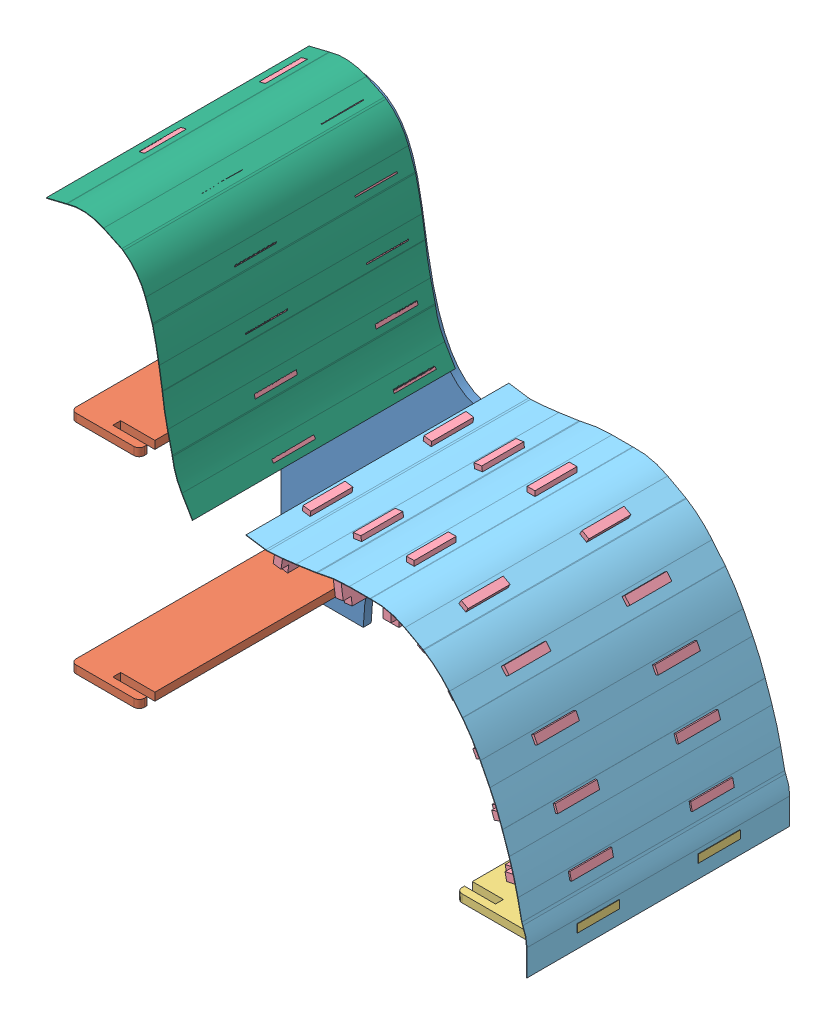
SolidWorks assembly chairA, configuration Default. Lengths in mm.
Overall size (2400 1520.6 565).
21 component instances, 6 part files, 62 mates.
Components (placement in the parent):
- chair-3: chair [Default] at origin size (892.39 905.44 15)
- chair-4: chair [Default] at (0 0 385) size (892.39 905.44 15) (hidden)
- base1-1: base1 [Default] at (0 0 400) size (130 15 430)
- base1-2: base1 [Default] at (0 415 400) size (130 15 430)
- base2-1: base2 [Default] at (0 0 400) size (170 15 430)
- coverSupport-1: coverSupport [Default] x (-1 0 0) z (0 0 -1) size (96.04 34.42 400)
- coverSupport-4: coverSupport [Default] at (34.0048 -123.247 400) x (-0.858521 -0.512778 0) z (0 0 1) size (96.04 34.42 400)
- coverSupport-5: coverSupport [Default] at (52.0991 -142.8628 400) x (-0.777508 -0.628873 0) z (0 0 1) size (96.04 34.42 400)
- coverSupport-7: coverSupport [Default] at (113.3609 -210.8477 400) x (-0.624811 -0.780776 0) z (0 0 1) size (96.04 34.42 400)
- coverSupport-8: coverSupport [Default] at (313.0867 -343.4559 400) x (-0.286022 -0.958223 0) z (0 0 1) size (96.04 34.42 400)
- coverSupport-10: coverSupport [Default] at (656.2813 -398.8647 400) x (0.217755 -0.976003 0) z (0 0 1) size (96.04 34.42 400)
- coverSupport-11: coverSupport [Default] at (674.4375 -392.1959 400) x (0.346446 -0.93807 0) z (0 0 1) size (96.04 34.42 400)
- coverSupport-13: coverSupport [Default] at (317.1284 -414.5841 400) x (0.060853 -0.998147 0) z (0 0 1) size (96.04 34.42 400)
- coverSupport-17: coverSupport [Default] at (-420.7027 22.5592 400) x (-0.737008 -0.675884 0) z (0 0 1) size (96.04 34.42 400)
- coverSupport-18: coverSupport [Default] at (-570.9691 355.3696 400) x (-0.904457 -0.426564 0) z (0 0 1) size (96.04 34.42 400)
- coverSupport-19: coverSupport [Default] at (-605.6475 516.2189 400) x (-0.933201 -0.359355 0) z (0 0 1) size (96.04 34.42 400)
- coverSupport-20: coverSupport [Default] at (-576.6639 460.0885 400) x (-0.85224 -0.523151 0) z (0 0 1) size (96.04 34.42 400)
- coverSupport-21: coverSupport [Default] at (-149.7762 65.2605 400) x (-0.23237 -0.972627 0) z (0 0 1) size (96.04 34.42 400)
- coverSupport-22: coverSupport [Default] at (345.2494 53.4414 400) x (0.433903 -0.900959 0) z (0 0 1) size (96.04 34.42 400)
- thinLowerCover-2: thinLowerCover [Default] at (-1 -9.5 -50) size (534.69 476.33 500)
- Part1^chairA-1: Part1^chairA [Default] at (0 0 15) size (278.66 406.87 500) (virtual)
Mates (geometry in assembly coordinates):
- Distance3: distance = 400 mm anti-aligned: plane of chair-3 through (445 0 0) normal (0 0 -1); plane of chair-4 through (445 0 400) normal (0 0 1)
- Concentric1: concentric aligned: circle of chair-3; circle of chair-4
- InPlace4: in place: plane of ? through (445 0 400) normal (0 0 1); plane of ? through (0 0 400) normal (0 0 1); moOrthogonalPlaneRef_w of ? through (445 0 400) normal (0 0 1); plane of ? through (0 0 400) normal (0 1 0); plane of ? through (445 0 400) normal (0 0 1); plane of ? through (0 0 400) normal (1 0 0); plane of chair-4 through (445 0 400) normal (0 0 1); unknown of ?
- Coincident15: coincident aligned: plane of chair-4; plane of base1-1
- Coincident16: coincident aligned: moOrthogonalPlaneRef_w of chair-4 through (0 0 400) normal (0 1 0); plane of base1-1 through (0 0 400) normal (0 1 0)
- Coincident17: coincident anti-aligned: moOrthogonalPlaneRef_w of chair-4 through (0 0 400) normal (-1 0 0); plane of base1-1 through (0 0 400) normal (1 0 0)
- Parallel3: parallel aligned: line of chair-3 through (0 0 15) axis (1 0 0); line of chair-4 through (0 0 400) axis (1 0 0)
- Coincident19: coincident aligned: plane of chair-4 through (0 808.1674 400) normal (-1 0 0); plane of base1-2 through (0 480 415) normal (-1 0 0)
- Distance4: distance = 15 mm aligned: plane of chair-4 through (445 0 400) normal (0 0 1); plane of base1-2 through (0 415 415) normal (0 0 1)
- Distance5: distance = 400 mm anti-aligned: plane of base1-1 through (0 65 415) normal (0 1 0); plane of base1-2 through (0 465 415) normal (0 -1 0)
- InPlace7: in place: plane of ? through (445 0 400) normal (0 0 1); plane of ? through (0 0 400) normal (0 0 1); plane of ? through (445 0 400) normal (0 0 1); plane of ? through (0 0 400) normal (0 1 0); plane of ? through (445 0 400) normal (0 0 1); plane of ? through (0 0 400) normal (1 0 0); plane of chair-4 through (445 0 400) normal (0 0 1); unknown of ?
- Coincident30: coincident aligned: plane of chair-4; plane of base2-1
- Coincident31: coincident aligned: moOrthogonalPlaneRef_w of chair-4 through (0 0 400) normal (0 1 0); plane of base2-1 through (0 0 400) normal (0 1 0)
- Coincident32: coincident anti-aligned: moOrthogonalPlaneRef_w of chair-4 through (0 0 400) normal (-1 0 0); plane of base2-1 through (0 0 400) normal (1 0 0)
- InPlace9: in place: plane of chair-3 through (445 0 0) normal (0 0 -1); plane of coverSupport-1 through (0 0 0) normal (0 0 -1); plane of chair-3 through (445 0 0) normal (0 0 -1); plane of coverSupport-1 through (0 0 0) normal (0 1 0); plane of chair-3 through (445 0 0) normal (0 0 -1); plane of coverSupport-1 through (0 0 0) normal (-1 0 0); plane of chair-3 through (445 0 0) normal (0 0 -1); unknown of coverSupport-1
- Coincident36: coincident aligned: plane of chair-3; plane of coverSupport-1
- Coincident37: coincident aligned: moOrthogonalPlaneRef_w of chair-3 through (0 0 0) normal (0 1 0); plane of coverSupport-1 through (0 0 0) normal (0 1 0)
- Coincident38: coincident anti-aligned: moOrthogonalPlaneRef_w of chair-3 through (0 0 0) normal (1 0 0); plane of coverSupport-1 through (0 0 0) normal (-1 0 0)
- Coincident45: coincident anti-aligned: plane of chair-3 through (16.6393 -72.379 15) normal (-0.323076 0.946373 0); plane of coverSupport-4 through (852.4203 212.9431 -87.1844) normal (0.323076 -0.946373 0)
- Coincident46: coincident aligned: plane of chair-3 through (445 0 0) normal (0 0 -1); plane of coverSupport-4 through (416.0467 104.9394 0) normal (0 0 -1)
- Coincident47: coincident anti-aligned: plane of chair-3 through (768.6943 257.0068 15) normal (0.946373 0.323076 0); plane of coverSupport-4 through (808.2715 141.0751 0) normal (-0.946373 -0.323076 0)
- Coincident48: coincident anti-aligned: plane of chair-3 through (27.7245 -94.9567 15) normal (-0.453478 0.891267 0); plane of coverSupport-5 through (814.8396 305.5284 -87.1844) normal (0.453478 -0.891267 0)
- Coincident49: coincident aligned: plane of chair-3 through (445 0 0) normal (0 0 -1); plane of coverSupport-5 through (398.0901 136.9858 0) normal (0 0 -1)
- Coincident50: coincident anti-aligned: plane of chair-3 through (725.7303 337.3274 15) normal (0.891267 0.453478 0); plane of coverSupport-5 through (781.2818 228.1462 0) normal (-0.891267 -0.453478 0)
- Coincident56: coincident anti-aligned: plane of chair-3 through (668.5423 402.451 15) normal (0.77349 0.633809 0); plane of coverSupport-7 through (746.1846 307.6977 0) normal (-0.77349 -0.633809 0)
- Coincident57: coincident anti-aligned: plane of chair-3 through (79.2933 -169.2722 15) normal (-0.633809 0.77349 0); plane of coverSupport-7 through (762.3939 390.4707 -87.1844) normal (0.633809 -0.77349 0)
- Coincident58: coincident aligned: plane of chair-3 through (445 0 0) normal (0 0 -1); plane of coverSupport-7 through (391.4016 136.5978 0) normal (0 0 -1)
- Coincident59: coincident aligned: plane of chair-3 through (445 0 0) normal (0 0 -1); plane of coverSupport-8 through (440.3666 82.9533 0) normal (0 0 -1)
- Coincident60: coincident anti-aligned: plane of chair-3 through (597.4411 433.3995 15) normal (0.478998 0.877816 0); plane of coverSupport-8 through (704.9745 374.7217 0) normal (-0.478998 -0.877816 0)
- Coincident61: coincident anti-aligned: plane of chair-3 through (252.7364 -310.5245 15) normal (0.877816 -0.478998 0); plane of coverSupport-8 through (675.759 464.7111 -87.1844) normal (-0.877816 0.478998 0)
- Coincident70: coincident aligned: plane of chair-3 through (445 0 0) normal (0 0 -1); plane of coverSupport-10 through (559.3802 35.4568 0) normal (0 0 -1)
- Coincident71: coincident anti-aligned: plane of chair-3 through (602.5335 -399.4062 15) normal (-0.999949 -0.010074 0); plane of coverSupport-10 through (593.6365 483.6902 -87.1844) normal (0.999949 0.010074 0)
- Coincident72: coincident anti-aligned: plane of chair-3 through (525.5443 418.0009 15) normal (-0.010074 0.999949 0); plane of coverSupport-10 through (648.0392 419.235 0) normal (0.010074 -0.999949 0)
- Coincident78: coincident anti-aligned: plane of coverSupport-11 through (494.2152 474.0301 -87.1844) normal (0.989601 0.14384 0); plane of chair-3 through (621.2459 -399.9273 15) normal (-0.989601 -0.14384 0)
- Coincident80: coincident anti-aligned: plane of chair-3 through (435.5292 399.817 15) normal (-0.14384 0.989601 0); plane of coverSupport-11 through (556.7564 417.4375 0) normal (0.14384 -0.989601 0)
- Coincident85: coincident aligned: plane of chair-4 through (445 0 400) normal (0 0 1); plane of coverSupport-11 through (674.4375 -392.1959 400) normal (0 0 1)
- Coincident86: coincident anti-aligned: plane of chair-3 through (317.0637 412.6775 15) normal (0.148003 0.988987 0); plane of coverSupport-13 through (438.2156 394.5469 0) normal (-0.148003 -0.988987 0)
- Coincident87: coincident aligned: plane of chair-3 through (445 0 0) normal (0 0 -1); plane of coverSupport-13 through (290.0487 29.5912 0) normal (0 0 -1)
- Coincident88: coincident anti-aligned: plane of chair-3 through (263.9698 -406.6288 15) normal (-0.988987 0.148003 0); plane of coverSupport-13 through (394.6773 466.7863 -87.1844) normal (0.988987 -0.148003 0)
- Coincident101: coincident aligned: plane of chair-3 through (445 0 0) normal (0 0 -1); plane of coverSupport-17 through (-92.7343 323.3277 0) normal (0 0 -1)
- Coincident102: coincident anti-aligned: plane of chair-3 through (221.8498 543.6042 15) normal (0.861427 0.507882 0); plane of coverSupport-17 through (284.0659 438.0785 0) normal (-0.861427 -0.507882 0)
- Coincident103: coincident anti-aligned: plane of chair-3 through (-448.0017 68.8613 15) normal (-0.507882 0.861427 0); plane of coverSupport-17 through (312.7597 517.393 -87.1844) normal (0.507882 -0.861427 0)
- Coincident104: coincident aligned: plane of chair-3 through (445 0 0) normal (0 0 -1); plane of coverSupport-18 through (-168.4856 545.1906 0) normal (0 0 -1)
- Coincident105: coincident anti-aligned: plane of chair-3 through (197.3169 662.1239 15) normal (0.97338 0.229195 0); plane of coverSupport-18 through (225.3936 542.8838 0) normal (-0.97338 -0.229195 0)
- Coincident106: coincident anti-aligned: plane of chair-3 through (-583.2885 407.6893 15) normal (-0.229195 0.97338 0); plane of coverSupport-18 through (276.344 610.1012 -87.1844) normal (0.229195 -0.97338 0)
- Coincident107: coincident aligned: plane of chair-3 through (445 0 0) normal (0 0 -1); plane of coverSupport-19 through (-190.3731 676.1319 0) normal (0 0 -1)
- Coincident111: coincident anti-aligned: plane of chair-3 through (-614.1121 569.2988 15) normal (-0.157479 0.987522 0); plane of coverSupport-19 through (258.0096 708.3749 -87.1844) normal (0.157479 -0.987522 0)
- Coincident114: coincident anti-aligned: plane of chair-3 through (232.37 773.9055 15) normal (-0.987522 -0.157479 0); plane of coverSupport-19 through (251.6614 652.9329 0) normal (0.987522 0.157479 0)
- Coincident115: coincident aligned: plane of chair-3 through (445 0 0) normal (0 0 -1); plane of coverSupport-20 through (-197.417 692.8905 0) normal (0 0 -1)
- Coincident116: coincident anti-aligned: plane of chair-3 through (153.3608 849.2227 15) normal (0.942386 0.334528 0); plane of coverSupport-20 through (194.3409 733.7794 0) normal (-0.942386 -0.334528 0)
- Coincident117: coincident anti-aligned: plane of chair-3 through (-594.645 510.7422 15) normal (-0.334528 0.942386 0); plane of coverSupport-20 through (237.6149 806.1775 -87.1844) normal (0.334528 -0.942386 0)
- Coincident118: coincident aligned: plane of chair-3 through (445 0 0) normal (0 0 -1); plane of coverSupport-21 through (-46.3713 498.0797 0) normal (0 0 -1)
- Coincident119: coincident anti-aligned: plane of chair-3 through (91.0004 856.7075 15) normal (0.429513 0.903061 0); plane of coverSupport-21 through (201.6263 804.0917 0) normal (-0.429513 -0.903061 0)
- Coincident120: coincident anti-aligned: plane of chair-3 through (-198.3161 88.3471 15) normal (-0.903061 0.429513 0); plane of coverSupport-21 through (181.0046 885.8772 -87.1844) normal (0.903061 -0.429513 0)
- Coincident121: coincident aligned: plane of chair-3 through (445 0 0) normal (0 0 -1); plane of coverSupport-22 through (152.1624 454.3683 0) normal (0 0 -1)
- Coincident122: coincident anti-aligned: plane of chair-3 through (32.259 819.2081 15) normal (-0.237101 0.971485 0); plane of coverSupport-22 through (151.2669 848.2533 0) normal (0.237101 -0.971485 0)
- Coincident123: coincident anti-aligned: plane of chair-3 through (293.0316 40.6971 15) normal (-0.971485 -0.237101 0); plane of coverSupport-22 through (83.6375 898.6555 -87.1844) normal (0.971485 0.237101 0)
- Lock3: lock: unknown of chair-3; unknown of thinLowerCover-2
- InPlace10: in place: plane of chair-3 through (445 0 15) normal (0 0 1); plane of Part1^chairA-1 through (0 0 15) normal (0 0 1); plane of chair-3 through (445 0 15) normal (0 0 1); plane of Part1^chairA-1 through (0 0 15) normal (0 1 0); plane of chair-3 through (445 0 15) normal (0 0 1); plane of Part1^chairA-1 through (0 0 15) normal (1 0 0); plane of chair-3 through (445 0 15) normal (0 0 1); unknown of Part1^chairA-1
- Coincident124: coincident aligned: plane of chair-3; plane of Part1^chairA-1
- Coincident125: coincident aligned: moOrthogonalPlaneRef_w of chair-3 through (0 0 15) normal (0 1 0); plane of Part1^chairA-1 through (0 0 15) normal (0 1 0)
- Coincident126: coincident anti-aligned: moOrthogonalPlaneRef_w of chair-3 through (0 0 15) normal (-1 0 0); plane of Part1^chairA-1 through (0 0 15) normal (1 0 0)
